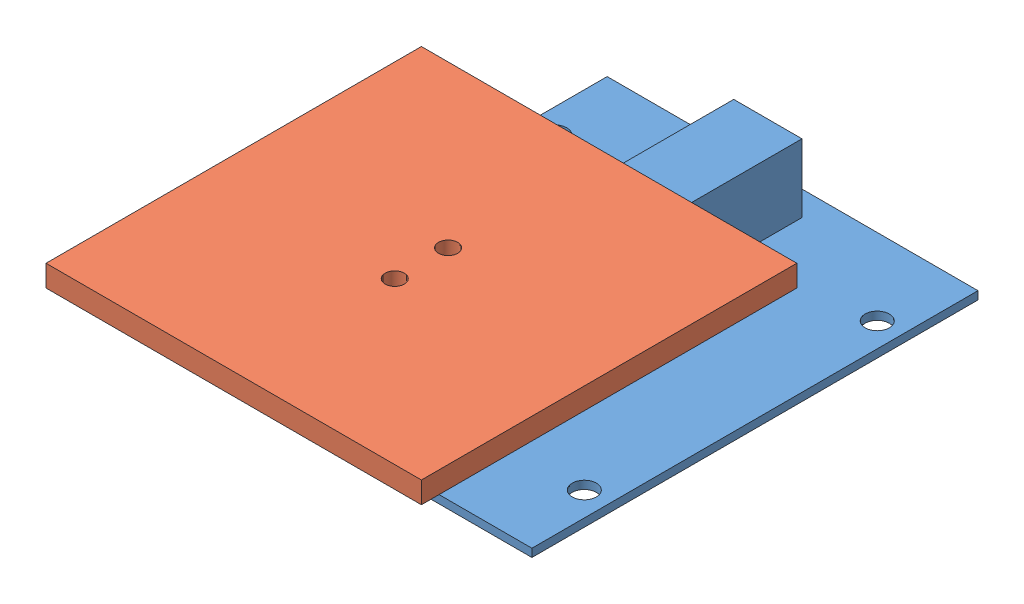
SolidWorks assembly Load Cell Assembly, configuration Default. Lengths in mm.
Overall size (69.85 23.2 103.99).
2 component instances, 2 part files, 4 mates.
Components (placement in the parent):
- Load Cell and Brace-1: Load Cell and Brace [Default] at (-9.1055 31.7162 92.7424) size (69 14.2 83)
- scalePlate_v2_234-1: scalePlate_v2_234 [Default] at (-9.5305 54.9162 113.7283) x (0 0 -1) z (-1 0 0) size (69.85 9 69.85)
Mates (geometry in assembly coordinates):
- Coincident1: coincident anti-aligned: plane of Load Cell and Brace-1 through (-9.1055 45.9162 92.7424) normal (0 1 0); plane of scalePlate_v2_234-1 through (-9.5305 45.9162 113.7283) normal (0 -1 0)
- Parallel1: parallel aligned: plane of Load Cell and Brace-1 through (19.0445 45.9162 89.3424) normal (0 0 1); plane of scalePlate_v2_234-1 through (-9.5305 50.9162 113.7283) normal (0 0 1)
- Width1: width: plane of Load Cell and Brace-1 through (31.7445 45.9162 89.3424) normal (1 0 0); plane of Load Cell and Brace-1 through (19.0445 45.9162 89.3424) normal (-1 0 0); cylinder of scalePlate_v2_234-1 through (25.3945 59.9676 83.7643) axis (0 -1 0) radius 1.7859
- Concentric3: concentric aligned: cylinder of Load Cell and Brace-1 through (25.3945 45.9162 73.8424) axis (0 -1 0) radius 1.5; cylinder of scalePlate_v2_234-1 through (25.3945 59.9676 73.8424) axis (0 -1 0) radius 1.7859
